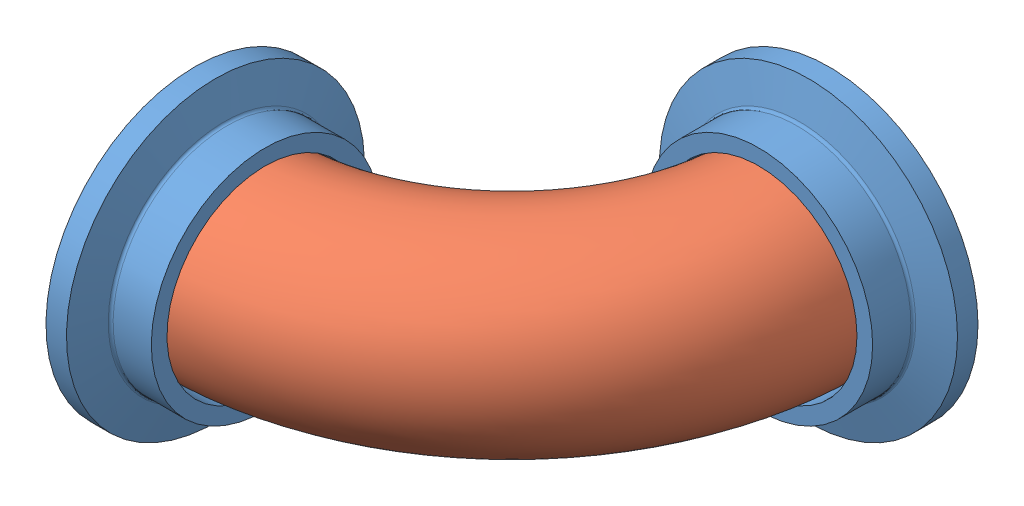
SolidWorks assembly 723017, configuration Default. Lengths in mm.
Overall size (62.36 55.36 70.1).
3 component instances, 2 part files, 8 mates.
Components (placement in the parent):
- 972301-1: 972301 [Default] x (0 0 1) z (1 0 0) size (9.4 39.88 39.88)
- 042197-2: 042197 [Default] at (0 0 4.318) size (50.8 25.4 50.8)
- 972301-2: 972301 [Default] at (-42.418 0 42.418) x (1 0 0) z (0 0.829279 0.558834) size (9.4 39.88 39.88)
Mates (geometry in assembly coordinates):
- Concentric1: concentric anti-aligned: circle of 972301-1; circle of 042197-2
- Coincident1: coincident anti-aligned: plane of 972301-1 through (0 -11.049 4.318) normal (0 0 1); plane of 042197-2 through (0 0 4.318) normal (0 0 -1)
- Coincident2: coincident aligned: plane of 972301-1 through (0 0 0) normal (0 0 1)
- Coincident3: coincident anti-aligned: plane of 972301-1 through (0 0 0) normal (0 -1 0)
- Coincident4: coincident aligned: plane of 972301-1 through (0 0 0) normal (1 0 0)
- Coincident5: coincident aligned: plane of 042197-2 through (0 0 4.318) normal (0 1 0)
- Concentric2: concentric aligned: circle of 042197-2; circle of 972301-2
- Coincident6: coincident anti-aligned: plane of 042197-2 through (-38.1 0 42.418) normal (-1 0 0); plane of 972301-2 through (-38.1 6.1746 33.2553) normal (1 0 0)
